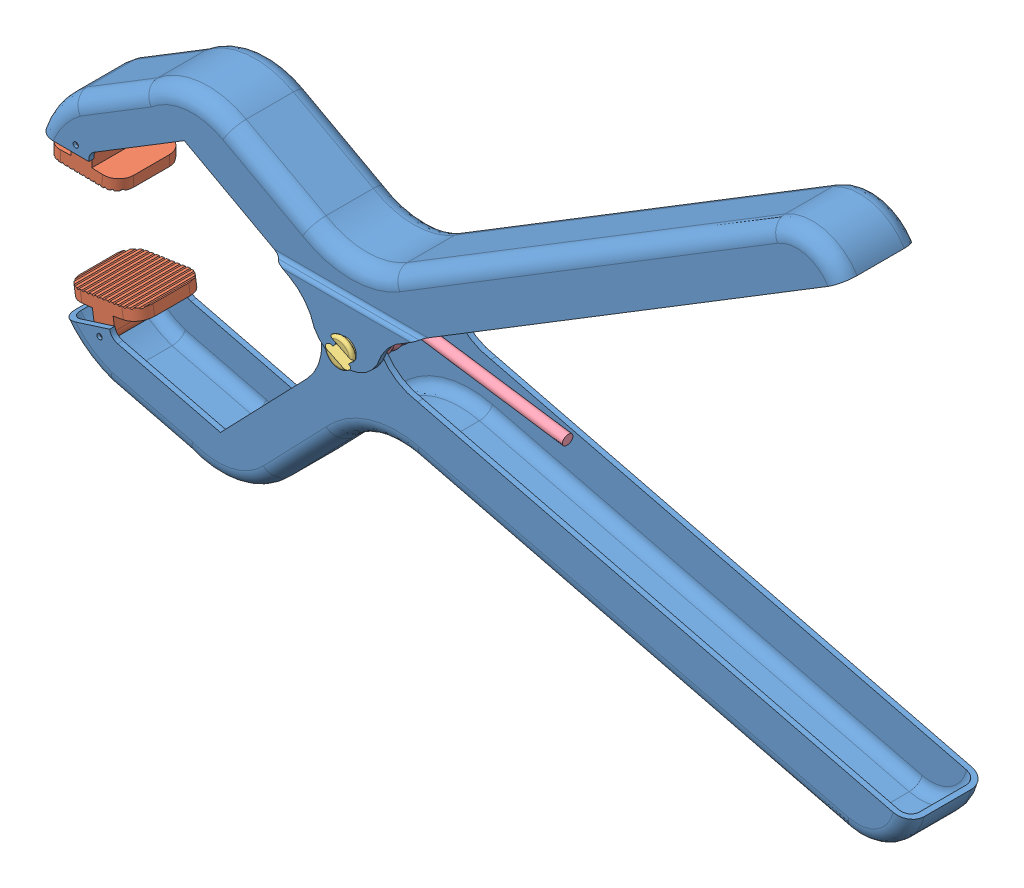
SolidWorks assembly lijmklem, configuration Default. Lengths in mm.
Overall size (167.97 138.6 19.55).
6 component instances, 4 part files, 10 mates.
Components (placement in the parent):
- klem-1: klem [configuratie 2] at (44.3048 68.2608 104.348) size (153.74 64.81 17)
- blokje-1: blokje [Default] at (-8.2528 69.7118 104.348) x (0.999945 -0.010475 0) z (0 0 1) size (14 6.54 14.3)
- middenstuk-1: middenstuk [Default] at (44.3048 68.2608 104.348) x (0 0 1) z (0.899048 -0.43785 0) size (19.55 6 6)
- klem-2: klem [configuratie 1] at (44.3048 68.2608 104.348) x (0.953558 0.301208 0) z (0 0 -1) size (153.74 64.81 15.37)
- blokje-2: blokje [Default] at (-4.48 51.2586 104.348) x (-0.988918 -0.148462 0) z (0 0 1) size (14 6.54 14.3)
- veer-1: veer [Default] at (44.3048 68.2608 99.848) x (0.98935 -0.145555 0) z (-0.145555 -0.98935 0) size (33.68 10.8 23.97)
Mates (geometry in assembly coordinates):
- Concentric1: concentric: cylinder of klem-1 through (-8.1952 75.2115 91.848) axis (0 0 1) radius 0.5; circle of blokje-1
- Coincident1: coincident: plane of klem-1 through (44.3048 68.2608 104.348) normal (0 0 1); plane of blokje-1 through (-8.2528 69.7118 104.348) normal (0 0 1)
- Concentric2: concentric: cylinder of klem-1 through (44.3048 68.2608 91.848) axis (0 0 1) radius 2; cylinder of middenstuk-1 through (44.3048 68.2608 94.8462) axis (0 0 -1) radius 2
- Coincident2: coincident: plane of klem-1 through (44.3048 68.2608 104.348) normal (0 0 1); plane of middenstuk-1 through (44.3048 68.2608 104.348) normal (0 0 1)
- Concentric4: concentric: cylinder of middenstuk-1 through (44.3048 68.2608 94.8462) axis (0 0 -1) radius 2; cylinder of klem-2 through (44.3048 68.2608 116.848) axis (0 0 -1) radius 2
- Coincident3: coincident: plane of klem-1 through (59.8787 65.8235 111.848) normal (0 0 -1); plane of klem-2 through (44.3048 68.2608 111.848) normal (0 0 1)
- Concentric5: concentric: cylinder of klem-2 through (-3.6634 45.8195 116.848) axis (0 0 -1) radius 0.5; circle of blokje-2
- Coincident4: coincident: plane of blokje-1 through (-8.2528 69.7118 104.348) normal (0 0 1); plane of blokje-2 through (-4.48 51.2586 104.348) normal (0 0 1)
- Concentric6: concentric: cylinder of middenstuk-1 through (44.3048 68.2608 94.8462) axis (0 0 -1) radius 2; circle of veer-1
- Distance1: distance = 2 mm: plane of veer-1 through (44.3048 68.2608 99.848) normal (0 0 1); plane of klem-2 through (44.3048 68.2608 97.848) normal (0 0 1)
